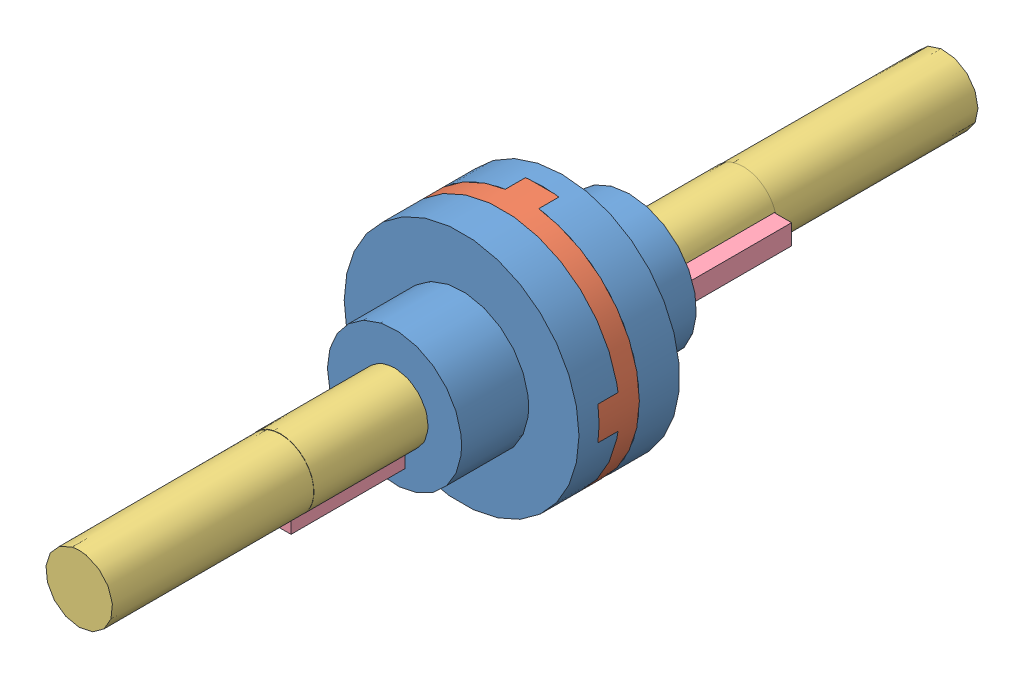
SolidWorks assembly oldham coupling, configuration Default. Lengths in mm.
Overall size (35 35 129).
7 component instances, 4 part files, 16 mates.
Components (placement in the parent):
- s1-1: s1 [Default] at (24.9447 23.3585 9.136) x (1 0 0) z (0 -1 0) size (35 16 35)
- s2-1: s2 [Default] at (24.9447 23.3585 25.136) size (35 35 9)
- s1-2: s1 [Default] at (24.9447 23.3585 44.136) x (0 -1 0) z (1 0 0) size (35 16 35)
- s3-1: s3 [Default] at (24.9447 23.3585 22.136) x (-1 0 0) z (0 0 -1) size (10 10 60)
- s4-1: s4 [Default] at (29.1331 21.7173 -7.864) size (3 3 30)
- s3-2: s3 [Default] at (24.9447 23.3585 31.136) x (0 1 0) z (0 0 1) size (10 10 60)
- s4-2: s4 [Default] at (26.5216 19.1702 31.136) x (-1 0 0) z (0 0 1) size (3 3 30)
Mates (geometry in assembly coordinates):
- Coincident1: coincident anti-aligned: circle of s1-1; circle of s2-1
- Coincident2: coincident anti-aligned: circle of s2-1; circle of s1-2
- Concentric1: concentric anti-aligned: circle of s1-1; circle of s3-1
- Parallel2: parallel anti-aligned: plane of s1-1 through (32.1331 21.8585 29.136) normal (-1 0 0); plane of s3-1 through (26.9199 23.3585 -7.864) normal (1 0 0)
- Coincident6: coincident anti-aligned: plane of s2-1 through (24.9447 23.3585 22.136) normal (0 0 -1); plane of s3-1 through (24.9447 23.3585 22.136) normal (0 0 1)
- Parallel4: parallel aligned: plane of s3-1 through (26.9199 23.3585 -7.864) normal (1 0 0); plane of s4-1 through (32.1331 21.7173 22.136) normal (1 0 0)
- Coincident9: coincident anti-aligned: plane of s3-1 through (24.9447 23.3585 -7.864) normal (0 0 1); plane of s4-1 through (29.1331 21.7173 -7.864) normal (0 0 -1)
- Coincident10: coincident anti-aligned: plane of s1-1 through (32.1331 21.8585 29.136) normal (-1 0 0); plane of s4-1 through (32.1331 21.7173 22.136) normal (1 0 0)
- Parallel5: parallel anti-aligned: plane of s1-2 through (26.8045 16.2548 24.136) normal (-0.050317 0.998733 0); plane of s3-2 through (25.0441 21.3859 61.136) normal (0.050317 -0.998733 0)
- Coincident12: coincident anti-aligned: plane of s2-1 through (24.9447 23.3585 31.136) normal (0 0 1); plane of s3-2 through (24.9447 23.3585 31.136) normal (0 0 -1)
- Concentric2: concentric anti-aligned: circle of s1-2; circle of s3-2
- Parallel6: parallel aligned: plane of s3-2 through (24.9447 21.3834 61.136) normal (0 -1 0); plane of s4-2 through (26.5216 16.1702 61.136) normal (0 -1 0)
- Coincident14: coincident anti-aligned: plane of s3-2 through (24.9447 23.3585 61.136) normal (0 0 -1); plane of s4-2 through (26.5216 19.1702 61.136) normal (0 0 1)
- Coincident15: coincident anti-aligned: plane of s1-2 through (26.4447 16.1702 24.136) normal (0 1 0); plane of s4-2 through (26.5216 16.1702 61.136) normal (0 -1 0)
- Coincident19: coincident: line of s2-1 through (42.2652 25.8585 31.136) axis (0 0 -1); moEndPointRef_w of s1-2
- Coincident20: coincident: unknown of s1-1; line of s2-1 through (22.4447 40.6791 22.136) axis (0 0 1)
